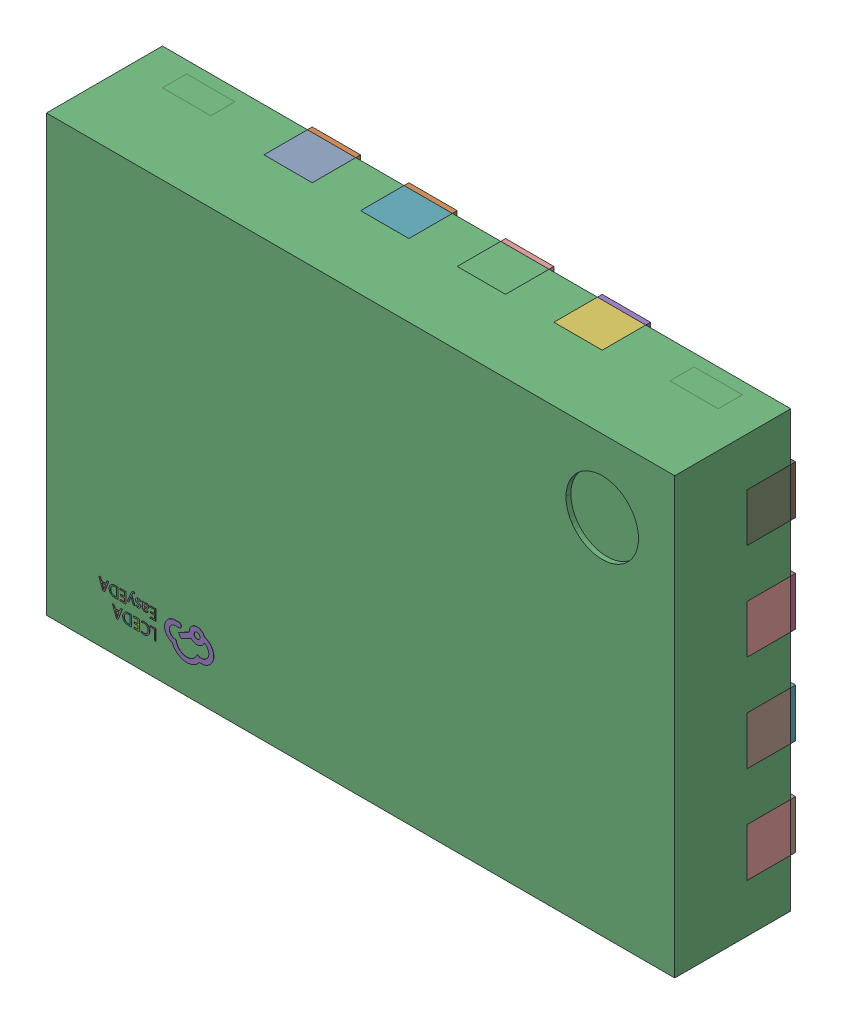
SolidWorks assembly U26, configuration Défaut. Lengths in mm.
Overall size (2.6 1.8 0.5).
4 component instances, 1 part files, 0 mates.
Components (placement in the parent):
- HD3SS3202RSVR-1: HD3SS3202RSVR [Défaut] at (74.3687 -28.6753 -1.6) x (-1 0 0) z (0 0 1) size (2.6 1.8 0.5)
  - U1.step-1: U1.step [Défaut] at (5.0775 -6.7805 1.6001) size (2.6 1.8 0.5)
    - UQFN-16_L2.6-W1.8-P0.40-BL.step-1: UQFN-16_L2.6-W1.8-P0.40-BL.step [Défaut] at origin size (2.6 1.8 0.5)
      - COMPOUND.step-1: COMPOUND.step [Défaut] at origin size (2.6 1.8 0.5)
